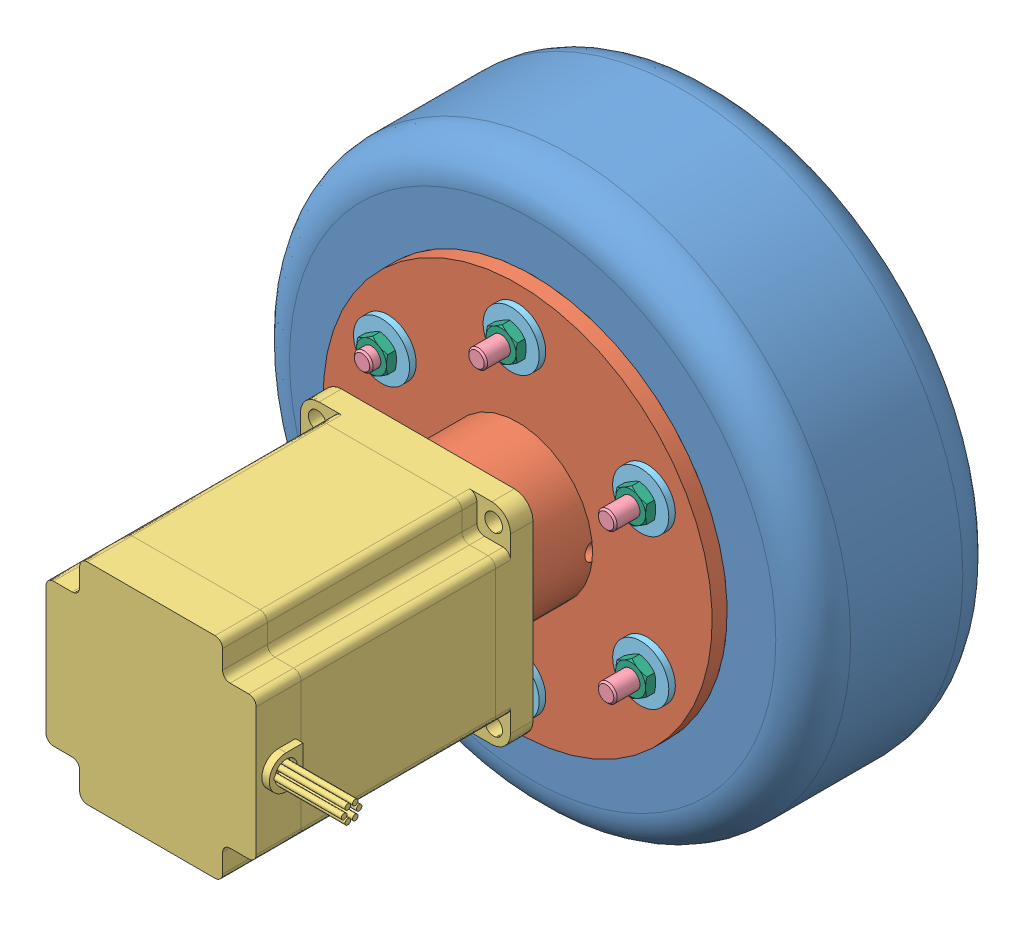
SolidWorks assembly new_wheel_flange_assembly, configuration Default. Lengths in mm.
Overall size (150 150 152).
21 component instances, 6 part files, 20 mates.
Components (placement in the parent):
- final_wheel_original-1: final_wheel_original [Default] at origin size (150 150 50)
- flange-1: flange [Default] at (0 0 29) x (-0.5 0.866025 0) z (0 0 1) size (104 104 46)
- NEMA 23-1: NEMA 23 [Default] at (0 0 127) x (1 0 0) z (0 1 0) size (76.2 99 56.2)
- IS 1364 HHS(Grade A)- M5 x 50-N-1: IS 1364 HHS(Grade A)- M5 x 50-N [IS 1364 HHS(Grade A)- M5 x 50-N] at (34.641 -20 -13.5) x (0 0 1) z (-1 0 0) size (53.5 9.24 8)
- IS 1364 HHS(Grade A)- M5 x 50-N-2: IS 1364 HHS(Grade A)- M5 x 50-N [IS 1364 HHS(Grade A)- M5 x 50-N] at (0 -40 -13.5) x (0 0 1) z (-0.626516 0.779409 0) size (53.5 9.24 8)
- IS 1364 HHS(Grade A)- M5 x 50-N-3: IS 1364 HHS(Grade A)- M5 x 50-N [IS 1364 HHS(Grade A)- M5 x 50-N] at (-34.641 20 -17.5405) x (0 0 1) z (-1 0 0) size (53.5 9.24 8)
- IS 1364 HHS(Grade A)- M5 x 50-N-4: IS 1364 HHS(Grade A)- M5 x 50-N [IS 1364 HHS(Grade A)- M5 x 50-N] at (-34.641 -20 -13.5) x (0 0 1) z (-1 0 0) size (53.5 9.24 8)
- IS 1364 HHS(Grade A)- M5 x 50-N-5: IS 1364 HHS(Grade A)- M5 x 50-N [IS 1364 HHS(Grade A)- M5 x 50-N] at (34.641 20 -13.5) x (0 0 1) z (-1 0 0) size (53.5 9.24 8)
- IS 1364 HHS(Grade A)- M5 x 50-N-7: IS 1364 HHS(Grade A)- M5 x 50-N [IS 1364 HHS(Grade A)- M5 x 50-N] at (0 40 -13.5) x (0 0 1) z (-1 0 0) size (53.5 9.24 8)
- B18.22M - Plain washer, 5 mm, regular-7: B18.22M - Plain washer, 5 mm, regular [B18.22M - Plain washer, 5 mm, regular] at (34.641 -20 29) x (0 0 -1) z (0.996253 -0.086488 0) size (1.75 15 15)
- B18.2.4.5M - Hex jam nut,  M5 x 0.8 --D-N-1: B18.2.4.5M - Hex jam nut,  M5 x 0.8 --D-N [B18.2.4.5M - Hex jam nut,  M5 x 0.8 --D-N] at (34.641 -20 33.45) size (8 9.24 2.7)
- B18.2.4.5M - Hex jam nut,  M5 x 0.8 --D-N-2: B18.2.4.5M - Hex jam nut,  M5 x 0.8 --D-N [B18.2.4.5M - Hex jam nut,  M5 x 0.8 --D-N] at (0 -40 33.45) x (0.5 -0.866025 0) z (0 0 1) size (8 9.24 2.7)
- B18.2.4.5M - Hex jam nut,  M5 x 0.8 --D-N-3: B18.2.4.5M - Hex jam nut,  M5 x 0.8 --D-N [B18.2.4.5M - Hex jam nut,  M5 x 0.8 --D-N] at (-34.641 -20 33.45) x (-0.5 -0.866025 0) z (0 0 1) size (8 9.24 2.7)
- B18.2.4.5M - Hex jam nut,  M5 x 0.8 --D-N-4: B18.2.4.5M - Hex jam nut,  M5 x 0.8 --D-N [B18.2.4.5M - Hex jam nut,  M5 x 0.8 --D-N] at (-34.641 20 33.45) x (-1 0 0) z (0 0 1) size (8 9.24 2.7)
- B18.2.4.5M - Hex jam nut,  M5 x 0.8 --D-N-5: B18.2.4.5M - Hex jam nut,  M5 x 0.8 --D-N [B18.2.4.5M - Hex jam nut,  M5 x 0.8 --D-N] at (0 40 33.45) x (-0.5 0.866025 0) z (0 0 1) size (8 9.24 2.7)
- B18.2.4.5M - Hex jam nut,  M5 x 0.8 --D-N-6: B18.2.4.5M - Hex jam nut,  M5 x 0.8 --D-N [B18.2.4.5M - Hex jam nut,  M5 x 0.8 --D-N] at (34.641 20 33.45) x (0.5 0.866025 0) z (0 0 1) size (8 9.24 2.7)
- B18.22M - Plain washer, 5 mm, regular-8: B18.22M - Plain washer, 5 mm, regular [B18.22M - Plain washer, 5 mm, regular] at (0 -40 29) x (0 0 -1) z (0.423225 -0.906024 0) size (1.75 15 15)
- B18.22M - Plain washer, 5 mm, regular-9: B18.22M - Plain washer, 5 mm, regular [B18.22M - Plain washer, 5 mm, regular] at (-34.641 -20 29) x (0 0 -1) z (-0.573028 -0.819536 0) size (1.75 15 15)
- B18.22M - Plain washer, 5 mm, regular-10: B18.22M - Plain washer, 5 mm, regular [B18.22M - Plain washer, 5 mm, regular] at (-34.641 20 29) x (0 0 -1) z (-0.996253 0.086488 0) size (1.75 15 15)
- B18.22M - Plain washer, 5 mm, regular-11: B18.22M - Plain washer, 5 mm, regular [B18.22M - Plain washer, 5 mm, regular] at (0 40 29) x (0 0 -1) z (-0.423225 0.906024 0) size (1.75 15 15)
- B18.22M - Plain washer, 5 mm, regular-12: B18.22M - Plain washer, 5 mm, regular [B18.22M - Plain washer, 5 mm, regular] at (34.641 20 29) x (0 0 -1) z (0.573028 0.819536 0) size (1.75 15 15)
Mates (geometry in assembly coordinates):
- Concentric3: concentric aligned: cylinder of final_wheel_original-1 through (0 0 25) axis (0 0 -1) radius 20; cylinder of flange-1 through (0 0 4) axis (0 0 -1) radius 20
- Coincident2: coincident anti-aligned: plane of final_wheel_original-1 through (0 0 25) normal (0 0 1); plane of flange-1 through (-45.0333 -26 25) normal (0 0 -1)
- Concentric4: concentric anti-aligned: cylinder of final_wheel_original-1 through (-34.641 -20 -25) axis (0 0 1) radius 2.5; cylinder of flange-1 through (-34.641 -20 50.001) axis (0 0 -1) radius 2.5
- Concentric5: concentric anti-aligned: cylinder of flange-1 through (0 0 50) axis (0 0 -1) radius 4; cylinder of NEMA 23-1 through (0 0 28) axis (0 0 1) radius 3.175
- Distance1: distance = 3 mm anti-aligned: plane of flange-1 through (0 0 50) normal (0 0 1); plane of NEMA 23-1 through (0 0 53) normal (0 0 -1)
- Concentric6: concentric anti-aligned: cylinder of final_wheel_original-1 through (34.641 -20 -25) axis (0 0 1) radius 2.5; cylinder of IS 1364 HHS(Grade A)- M5 x 50-N-1 through (34.641 -20 -13.5) axis (0 0 -1) radius 2.5
- Concentric7: concentric anti-aligned: cylinder of final_wheel_original-1 through (0 -40 -25) axis (0 0 1) radius 2.5; cylinder of IS 1364 HHS(Grade A)- M5 x 50-N-2 through (0 -40 -13.5) axis (0 0 -1) radius 2.5
- Concentric8: concentric anti-aligned: cylinder of final_wheel_original-1 through (-34.641 20 -25) axis (0 0 1) radius 2.5; cylinder of IS 1364 HHS(Grade A)- M5 x 50-N-3 through (-34.641 20 -17.5405) axis (0 0 -1) radius 2.5
- Concentric9: concentric anti-aligned: cylinder of final_wheel_original-1 through (-34.641 -20 -25) axis (0 0 1) radius 2.5; cylinder of IS 1364 HHS(Grade A)- M5 x 50-N-4 through (-34.641 -20 -13.5) axis (0 0 -1) radius 2.5
- Concentric10: concentric anti-aligned: cylinder of final_wheel_original-1 through (34.641 20 -25) axis (0 0 1) radius 2.5; cylinder of IS 1364 HHS(Grade A)- M5 x 50-N-5 through (34.641 20 -13.5) axis (0 0 -1) radius 2.5
- Concentric11: concentric anti-aligned: cylinder of final_wheel_original-1 through (0 40 -25) axis (0 0 1) radius 2.5; cylinder of IS 1364 HHS(Grade A)- M5 x 50-N-7 through (0 40 -13.5) axis (0 0 -1) radius 2.5
- Coincident3: coincident anti-aligned: plane of final_wheel_original-1 through (0 0 -10) normal (0 0 -1); plane of IS 1364 HHS(Grade A)- M5 x 50-N-1 through (34.641 -15.3812 -10) normal (0 0 1)
- Coincident4: coincident anti-aligned: plane of final_wheel_original-1 through (0 0 -10) normal (0 0 -1); plane of IS 1364 HHS(Grade A)- M5 x 50-N-2 through (3.5999 -37.1062 -10) normal (0 0 1)
- Coincident5: coincident anti-aligned: plane of final_wheel_original-1 through (0 0 -10) normal (0 0 -1); plane of IS 1364 HHS(Grade A)- M5 x 50-N-7 through (0 44.6188 -10) normal (0 0 1)
- Coincident6: coincident anti-aligned: plane of final_wheel_original-1 through (0 0 -10) normal (0 0 -1); plane of IS 1364 HHS(Grade A)- M5 x 50-N-4 through (-34.641 -15.3812 -10) normal (0 0 1)
- Coincident7: coincident anti-aligned: plane of final_wheel_original-1 through (0 0 -10) normal (0 0 -1); plane of IS 1364 HHS(Grade A)- M5 x 50-N-5 through (34.641 24.6188 -10) normal (0 0 1)
- Concentric13: concentric anti-aligned: cylinder of IS 1364 HHS(Grade A)- M5 x 50-N-1 through (34.641 -20 -13.5) axis (0 0 -1) radius 2.5; cylinder of B18.22M - Plain washer, 5 mm, regular-7 through (34.641 -20 63.925) axis (0 0 1) radius 2.89
- Coincident9: coincident anti-aligned: plane of flange-1 through (0 0 29) normal (0 0 1); plane of B18.22M - Plain washer, 5 mm, regular-7 through (34.891 -17.1208 29) normal (0 0 -1)
- Coincident10: coincident anti-aligned: plane of B18.22M - Plain washer, 5 mm, regular-7 through (35.2897 -12.5281 30.75) normal (0 0 1); plane of B18.2.4.5M - Hex jam nut,  M5 x 0.8 --D-N-1 through (34.641 -15.3812 30.75) normal (0 0 -1)
- Concentric14: concentric anti-aligned: cylinder of IS 1364 HHS(Grade A)- M5 x 50-N-1 through (34.641 -20 -13.5) axis (0 0 -1) radius 2.5; cylinder of B18.2.4.5M - Hex jam nut,  M5 x 0.8 --D-N-1 through (34.641 -20 30.75) axis (0 0 1) radius 2.1
